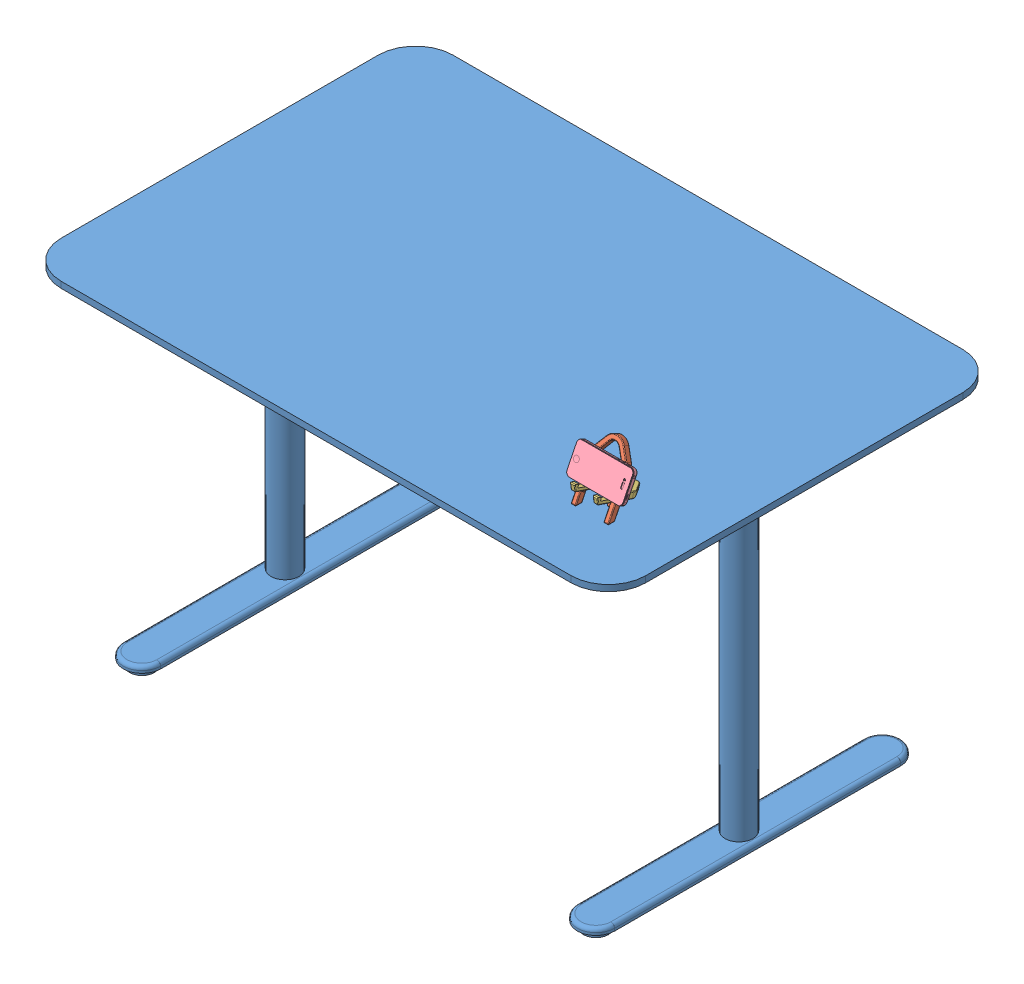
SolidWorks assembly Assem2, configuration Default. Lengths in mm.
Overall size (1193.8 818.51 800.1).
4 component instances, 4 part files, 9 mates.
Components (placement in the parent):
- Table-1: Table [Default] at origin size (1193.8 704.85 800.1)
- Outer-1: Outer [Default] at (431.8 -5.6796 262.7936) x (1 0 0) z (0 0.447214 0.894427) size (76.2 126.13 12.7)
- Inner-1: Inner [Default] at (431.8 37.6708 289.5204) x (1 0 0) z (0 0.945238 -0.326382) size (76.2 115.75 12.7)
- iPhone 4-1: iPhone 4 [Default<As Machined>] at (431.8 62.2248 248.3082) x (0 -0.894427 0.447214) z (0 0.447214 0.894427) size (60.83 116.46 9.42)
Mates (geometry in assembly coordinates):
- Concentric1: concentric: cylinder of Outer-1 through (393.7 31.2379 251.4343) axis (1 0 0) radius 3.175; cylinder of Inner-1 through (393.7 31.2379 251.4343) axis (1 0 0) radius 2.921
- Width1: width: plane of Outer-1 through (403.225 64.8811 227.5132) normal (1 0 0); plane of Outer-1 through (460.375 -5.6796 262.7936) normal (-1 0 0); plane of Inner-1 through (413.385 23.8408 210.556) normal (1 0 0); plane of Inner-1 through (450.215 23.8408 210.556) normal (-1 0 0)
- Coincident1: coincident: plane of Table-1 through (520.7 0 -323.85) normal (0 1 0); plane of Outer-1 through (393.7 0 274.1528) normal (0 -1 0)
- Distance1: distance = 127 mm: plane of Outer-1 through (469.9 79.5146 234.3955) normal (1 0 0); plane of Table-1 through (596.9 -12.7 -323.85) normal (1 0 0)
- Distance2: distance = 127 mm: line of Outer-1 through (461.899 2.2056 273.05) axis (1 0 0); plane of Table-1 through (-520.7 -12.7 400.05) normal (0 0 1)
- Tangent1: tangent: plane of Table-1 through (520.7 0 -323.85) normal (0 1 0); torus of Inner-1
- Coincident2: coincident: plane of Outer-1 through (431.8 94.1193 227.0931) normal (0 0.447214 0.894427); plane of iPhone 4-1 through (354.3285 95.5431 228.3332) normal (0 -0.447214 -0.894427)
- Width2: width: plane of iPhone 4-1 through (461.58 99.0418 235.3305) normal (1 0 0); plane of iPhone 4-1 through (345.629 60.6476 254.5276) normal (-1 0 0); plane of Outer-1 through (469.9 79.5146 234.3955) normal (1 0 0); plane of Outer-1 through (393.7 79.5146 234.3955) normal (-1 0 0)
- Coincident3: coincident: plane of Inner-1 through (393.7 33.8078 258.8771) normal (0 0.945238 -0.326382); line of iPhone 4-1 through (382.524 33.8552 259.0143) axis (1 0 0)
